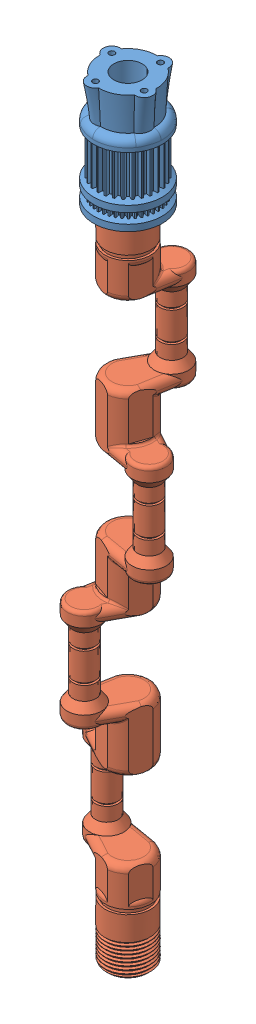
SolidWorks assembly cavity thread, configuration Default. Lengths in mm.
Overall size (97.45 675.01 97.45).
2 component instances, 2 part files, 2 mates.
Components (placement in the parent):
- fan belt extension-1: fan belt extension [Default] at (30.5123 10.6146 74.6978) size (60 101.1 60)
- Full Crank-1: Full Crank [Default] at (-187.7739 -159.1656 441.3968) x (0 -1 0) z (0.25224 0 0.967665) size (600 79.88 79.88)
Mates (geometry in assembly coordinates):
- Concentric2: concentric aligned: cylinder of fan belt extension-1 through (30.5123 10.6146 74.6978) axis (0 1 0) radius 12.3848; cylinder of Full Crank-1 through (30.5123 -84.3854 74.6978) axis (0 1 0) radius 20
- Distance3: distance = 25 mm aligned: plane of fan belt extension-1 through (30.5123 10.6146 74.6978) normal (0 -1 0); plane of Full Crank-1 through (30.5123 -14.3854 74.6978) normal (0 -1 0)
